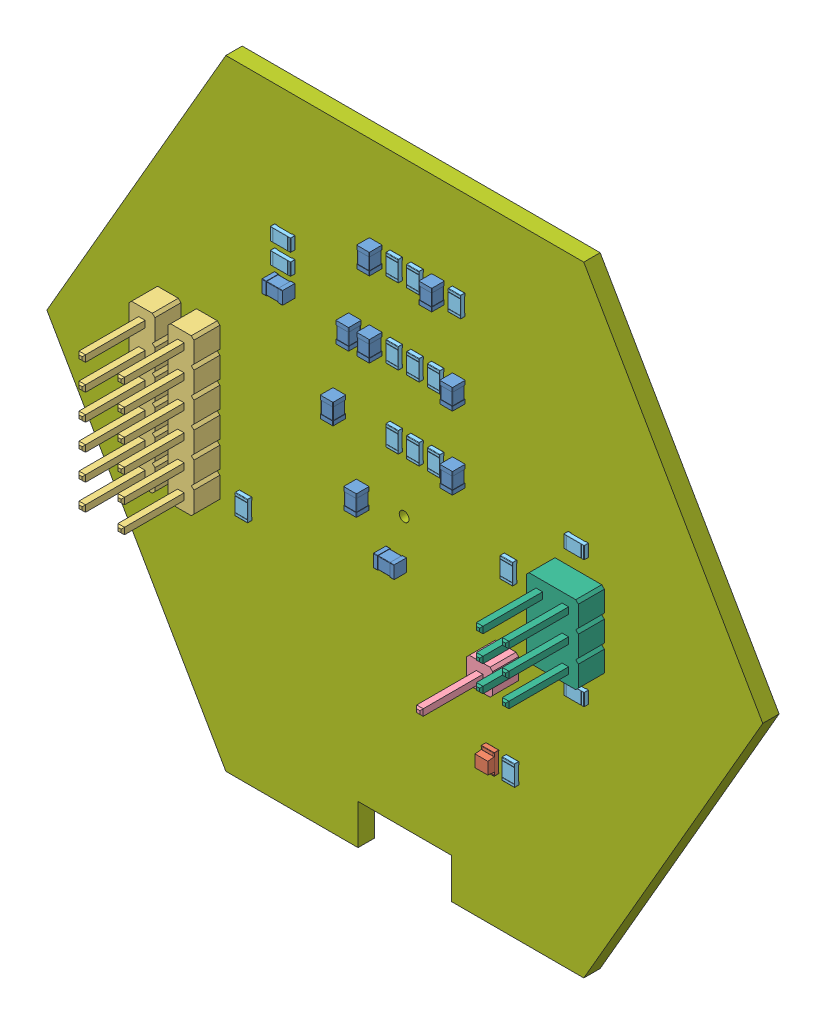
SolidWorks assembly SoundModulev1, configuration Default. Lengths in mm.
Overall size (70 60.62 11.54).
64 component instances, 7 part files, 0 mates.
Components (placement in the parent):
- SoundModulev1.step-1: SoundModulev1.step [Default] at origin size (70 60.62 11.54)
  - C_0805_2012Metric.step-1: C_0805_2012Metric.step [Default] at (121.7281 -81.8947 1.65) size (2 1.25 1.25)
    - SOLID.step-1: SOLID.step [Default] at origin size (2 1.25 1.25)
  - C_0805_2012Metric.step-2: C_0805_2012Metric.step [Default] at (118.4351 -78.0757 1.65) x (0 1 0) z (0 0 1) size (2 1.25 1.25)
    - SOLID.step-1: SOLID.step [Default] at origin size (2 1.25 1.25)
  - C_0805_2012Metric.step-3: C_0805_2012Metric.step [Default] at (127.8331 -71.4897 1.65) x (0 1 0) z (0 0 1) size (2 1.25 1.25)
    - SOLID.step-1: SOLID.step [Default] at origin size (2 1.25 1.25)
  - C_0805_2012Metric.step-4: C_0805_2012Metric.step [Default] at (116.1491 -71.4717 1.65) x (0 -1 0) z (0 0 1) size (2 1.25 1.25)
    - SOLID.step-1: SOLID.step [Default] at origin size (2 1.25 1.25)
  - C_0805_2012Metric.step-5: C_0805_2012Metric.step [Default] at (127.8331 -64.3777 1.65) x (0 1 0) z (0 0 1) size (2 1.25 1.25)
    - SOLID.step-1: SOLID.step [Default] at origin size (2 1.25 1.25)
  - C_0805_2012Metric.step-6: C_0805_2012Metric.step [Default] at (110.8241 -64.1147 1.65) size (2 1.25 1.25)
    - SOLID.step-1: SOLID.step [Default] at origin size (2 1.25 1.25)
  - C_0805_2012Metric.step-7: C_0805_2012Metric.step [Default] at (117.6731 -64.3777 1.65) x (0 1 0) z (0 0 1) size (2 1.25 1.25)
    - SOLID.step-1: SOLID.step [Default] at origin size (2 1.25 1.25)
  - C_0805_2012Metric.step-8: C_0805_2012Metric.step [Default] at (119.7051 -64.3777 1.65) x (0 1 0) z (0 0 1) size (2 1.25 1.25)
    - SOLID.step-1: SOLID.step [Default] at origin size (2 1.25 1.25)
  - C_0805_2012Metric.step-9: C_0805_2012Metric.step [Default] at (119.7051 -56.9937 1.65) x (0 1 0) z (0 0 1) size (2 1.25 1.25)
    - SOLID.step-1: SOLID.step [Default] at origin size (2 1.25 1.25)
  - C_0805_2012Metric.step-10: C_0805_2012Metric.step [Default] at (125.8011 -56.9937 1.65) x (0 -1 0) z (0 0 1) size (2 1.25 1.25)
    - SOLID.step-1: SOLID.step [Default] at origin size (2 1.25 1.25)
  - LED_0805_2012Metric.step-1: LED_0805_2012Metric.step [Default] at (131.1351 -94.0322 1.65) x (0 1 0) z (0 0 1) size (2 1.25 1.1)
    - SOLID-0.step-1: SOLID-0.step [Default] at origin size (2 1.25 1.1)
  - PinHeader_1x06_P2.54mm_Vertical.step-1: PinHeader_1x06_P2.54mm_Vertical.step [Default] at (103.1951 -84.4347 1.65) x (-1 0 0) z (0 0 1) size (2.54 15.24 11.54)
    - SOLID-1.step-1: SOLID-1.step [Default] at origin size (2.54 15.24 11.54)
  - PinHeader_1x06_P2.54mm_Vertical.step-2: PinHeader_1x06_P2.54mm_Vertical.step [Default] at (99.3851 -84.4347 1.65) x (-1 0 0) z (0 0 1) size (2.54 15.24 11.54)
    - SOLID-1.step-1: SOLID-1.step [Default] at origin size (2.54 15.24 11.54)
  - PinHeader_1x01_P2.54mm_Vertical.step-1: PinHeader_1x01_P2.54mm_Vertical.step [Default] at (132.4051 -85.1967 1.65) size (2.54 2.54 11.54)
    - SOLID-2.step-1: SOLID-2.step [Default] at origin size (2.54 2.54 11.54)
  - R_0805_2012Metric.step-1: R_0805_2012Metric.step [Default] at (107.0051 -84.6797 1.65) x (0 -1 0) z (0 0 1) size (2 1.2 0.45)
    - SOLID-3.step-1: SOLID-3.step [Default] at origin size (2 1.2 0.45)
  - R_0805_2012Metric.step-2: R_0805_2012Metric.step [Default] at (133.1036 -94.0322 1.65) x (0 1 0) z (0 0 1) size (2 1.2 0.45)
    - SOLID-3.step-1: SOLID-3.step [Default] at origin size (2 1.2 0.45)
  - R_0805_2012Metric.step-3: R_0805_2012Metric.step [Default] at (125.8011 -71.4897 1.65) x (0 1 0) z (0 0 1) size (2 1.2 0.45)
    - SOLID-3.step-1: SOLID-3.step [Default] at origin size (2 1.2 0.45)
  - R_0805_2012Metric.step-4: R_0805_2012Metric.step [Default] at (123.7691 -71.4897 1.65) x (0 -1 0) z (0 0 1) size (2 1.2 0.45)
    - SOLID-3.step-1: SOLID-3.step [Default] at origin size (2 1.2 0.45)
  - R_0805_2012Metric.step-5: R_0805_2012Metric.step [Default] at (110.8241 -62.0827 1.65) x (-1 0 0) z (0 0 1) size (2 1.2 0.45)
    - SOLID-3.step-1: SOLID-3.step [Default] at origin size (2 1.2 0.45)
  - R_0805_2012Metric.step-6: R_0805_2012Metric.step [Default] at (110.8241 -60.0507 1.65) size (2 1.2 0.45)
    - SOLID-3.step-1: SOLID-3.step [Default] at origin size (2 1.2 0.45)
  - R_0805_2012Metric.step-7: R_0805_2012Metric.step [Default] at (121.7371 -71.4897 1.65) x (0 -1 0) z (0 0 1) size (2 1.2 0.45)
    - SOLID-3.step-1: SOLID-3.step [Default] at origin size (2 1.2 0.45)
  - R_0805_2012Metric.step-8: R_0805_2012Metric.step [Default] at (125.8011 -64.3777 1.65) x (0 1 0) z (0 0 1) size (2 1.2 0.45)
    - SOLID-3.step-1: SOLID-3.step [Default] at origin size (2 1.2 0.45)
  - R_0805_2012Metric.step-9: R_0805_2012Metric.step [Default] at (123.7691 -64.3777 1.65) x (0 -1 0) z (0 0 1) size (2 1.2 0.45)
    - SOLID-3.step-1: SOLID-3.step [Default] at origin size (2 1.2 0.45)
  - R_0805_2012Metric.step-10: R_0805_2012Metric.step [Default] at (121.7371 -64.3777 1.65) x (0 1 0) z (0 0 1) size (2 1.2 0.45)
    - SOLID-3.step-1: SOLID-3.step [Default] at origin size (2 1.2 0.45)
  - R_0805_2012Metric.step-11: R_0805_2012Metric.step [Default] at (121.7371 -56.9937 1.65) x (0 -1 0) z (0 0 1) size (2 1.2 0.45)
    - SOLID-3.step-1: SOLID-3.step [Default] at origin size (2 1.2 0.45)
  - R_0805_2012Metric.step-12: R_0805_2012Metric.step [Default] at (123.7691 -56.9937 1.65) x (0 1 0) z (0 0 1) size (2 1.2 0.45)
    - SOLID-3.step-1: SOLID-3.step [Default] at origin size (2 1.2 0.45)
  - R_0805_2012Metric.step-13: R_0805_2012Metric.step [Default] at (127.8331 -56.9937 1.65) x (0 -1 0) z (0 0 1) size (2 1.2 0.45)
    - SOLID-3.step-1: SOLID-3.step [Default] at origin size (2 1.2 0.45)
  - PinHeader_2x03_P2.54mm_Vertical.step-1: PinHeader_2x03_P2.54mm_Vertical.step [Default] at (138.2471 -75.2907 1.65) size (5.08 7.62 11.54)
    - SOLID-4.step-1: SOLID-4.step [Default] at origin size (5.08 7.62 11.54)
  - R_0805_2012Metric.step-14: R_0805_2012Metric.step [Default] at (139.5261 -71.7347 1.65) x (-1 0 0) z (0 0 1) size (2 1.2 0.45)
    - SOLID-3.step-1: SOLID-3.step [Default] at origin size (2 1.2 0.45)
  - R_0805_2012Metric.step-15: R_0805_2012Metric.step [Default] at (139.5261 -84.1807 1.65) x (-1 0 0) z (0 0 1) size (2 1.2 0.45)
    - SOLID-3.step-1: SOLID-3.step [Default] at origin size (2 1.2 0.45)
  - R_0805_2012Metric.step-16: R_0805_2012Metric.step [Default] at (132.9131 -77.0687 1.65) x (0 -1 0) z (0 0 1) size (2 1.2 0.45)
    - SOLID-3.step-1: SOLID-3.step [Default] at origin size (2 1.2 0.45)
  - COMPOUND.step-1: COMPOUND.step [Default] at origin size (70 60.62 1.6)
